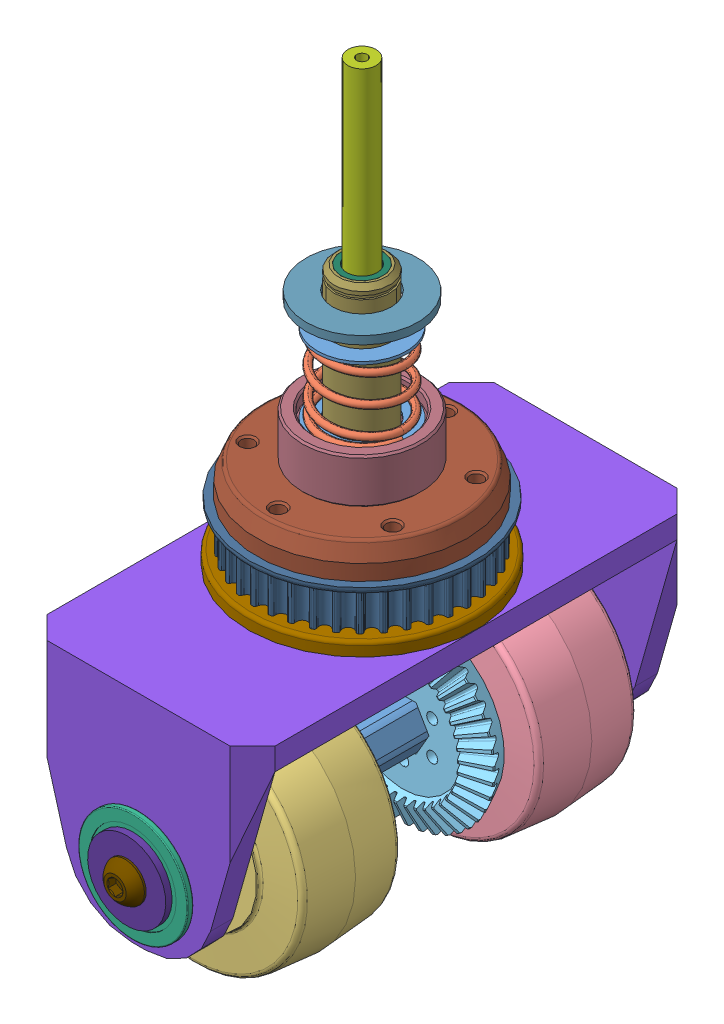
SolidWorks assembly 2018_swerve_module_asm, configuration Default. Lengths in mm.
Overall size (88.48 203.85 142.26).
33 component instances, 26 part files, 0 mates.
Components (placement in the parent):
- 2016_SWERVE_AXLE_RNM_RNM-1: 2016_SWERVE_AXLE_RNM_RNM [Default] x (1 0 0) z (0 0 -1) size (13.74 12.7 127)
- AM-2621_20T_1-25MOD_BEVEL_GEAR-1: AM-2621_20T_1-25MOD_BEVEL_GEAR [Default] at (0 25.321 0) x (1 0 0) z (0 0 -1) size (26.56 18.56 26.56)
- 217-4046-STEP-20141030-1: 217-4046-STEP-20141030 [Default] at (0 0 33.5534) x (0 0 1) z (-1 0 0) size (33.1 63.5 63.5)
- COLSON_WHEEL_MODIFIED-1: COLSON_WHEEL_MODIFIED [Default] at (0 0 -33.5788) x (0 0 1) z (-1 0 0) size (32.43 63.5 63.5)
- AM-2620_40T_1-25MOD_BEVEL_GEAR-1: AM-2620_40T_1-25MOD_BEVEL_GEAR [Default] at (0 0 -13.2049) x (0.866025 -0.5 0) z (-0.5 -0.866025 0) size (50.76 8.78 50.76)
- 217-4006-STEP-20140807-1: 217-4006-STEP-20140807 [Default] at (0 0 61.1187) size (31.12 31.12 7.94)
- 217-4006-STEP-20140807-2: 217-4006-STEP-20140807 [Default] at (0 0 -61.1187) x (-1 0 0) z (0 0 -1) size (31.12 31.12 7.94)
- 8MM_VERT_DRIVE_SHAFT-1: 8MM_VERT_DRIVE_SHAFT [Default] at (0 19.322 0) x (0 1 0) z (0 0 1) size (149.86 8 8)
- SWERVE_SADDLE-1: SWERVE_SADDLE [Default] at (0 38.1 0) x (0 0 1) z (-1 0 0) size (127 62.23 64.77)
- 38T_HTD_PULLEY_AZ_FLANGE-1: 38T_HTD_PULLEY_AZ_FLANGE [Default] at (0 48.26 0) x (0.866025 0 -0.5) z (-0.5 0 -0.866025) size (64.77 3.81 64.77)
- HTD_TB_PULLEY_38T_SWERVE-1: HTD_TB_PULLEY_38T_SWERVE [Default] at (0 59.51 0) x (-0.866025 0 0.5) z (0 -1 0) size (64 64 13)
- SWERVE_PIVOT_HUB_MOUNT-1: SWERVE_PIVOT_HUB_MOUNT [Default] at (0 117.14 0) x (0 -1 0) z (-1 0 0) size (27.43 59.69 59.69)
- SWERVE_PIVOT_HUB_TUBE-1: SWERVE_PIVOT_HUB_TUBE [Default] at (0 118.41 0) x (0 -1 0) z (0 0 1) size (75.56 15.88 15.88)
- TOPHAT_SLEEVE-1: TOPHAT_SLEEVE [Default] at (0 70.277 0) size (33.83 12.7 33.83)
- SWERVE_MOUNTING_HUB-1: SWERVE_MOUNTING_HUB [Default] at (0 109.647 0) x (0 -1 0) z (0 0 1) size (39.37 69.85 69.85) (hidden)
- AL_WASHER-1: AL_WASHER [Default] at (0 109.647 0) size (31.75 2.29 31.75)
- 5905K730_STL_NEEDLE-ROLLER_BRNG-1: 5905K730_STL_NEEDLE-ROLLER_BRNG [Default] at (0 114.41 0) x (1 0 0) z (0 -1 0) size (12 12 8)
- AM_0931-1: AM_0931 [Default] at (0 36.6 0) x (0 1 0) z (0 0 1) size (6 22 22)
- 91525A119-1: 91525A119 [Default] at (0 0 -65.0875) x (0 0 -1) z (0 1 0) size (1.78 22.23 22.23)
- 91525A119-2: 91525A119 [Default] at (0 0 65.0875) x (0 0 1) z (0 1 0) size (1.78 22.23 22.23)
- 98164A211-1: 98164A211 [Default] at (0 0 70.2183) size (11.17 11.22 17.34)
- 98164A211-2: 98164A211 [Default] at (0 0 -70.2183) x (-1 0 0) z (0 0 -1) size (11.17 11.22 17.34)
- STEEL_SHIM_WASHER-1: STEEL_SHIM_WASHER [Default] at (0 79.802 0) size (25.4 0.81 25.4)
- 9657K101_STEEL_COMPRESSION_SPRI-1: 9657K101_STEEL_COMPRESSION_SPRI [Default] at (0 80.6148 0) x (1 0 0) z (0 -1 0) size (25.14 23.85 22.11)
- STEEL_SHIM_WASHER-2: STEEL_SHIM_WASHER [Default] at (0 102.4842 0) size (25.4 0.81 25.4)
- 8MM_SHAFT_44T_HTD_PULLEY_ASM-1: 8MM_SHAFT_44T_HTD_PULLEY_ASM [Default] at (0 146.5405 0) x (-1 0 0) z (0 0 1) size (100.97 27.3 100.97)
  - 8MM_PULLEY_HUB-1: 8MM_PULLEY_HUB [Default] at origin size (22 26.54 19.05) (hidden)
  - HTD_TB_PULLEY_44T-1: HTD_TB_PULLEY_44T [Default] at (0 25.555 0) x (-1 0 0) z (0 -1 0) size (73.91 73.91 16.02) (hidden)
  - 44T_HTD_PULLEY_FLANGE-1: 44T_HTD_PULLEY_FLANGE [Default] at (0 9.5302 0) x (0.5 0 0.866025) z (-0.866025 0 0.5) size (73.91 1.75 73.91) (hidden)
  - 217-2736_20121205_ASM-1: 217-2736_20121205_ASM [Default] at (-4.5154 5.7531 -2.6156) x (-1 0 0) z (0 1 0) size (25.39 25.4 6.35)
    - 217-2736_20121205_1_ASM-1: 217-2736_20121205_1_ASM [Default] at origin size (25.39 25.4 6.35)
      - 217-2736-001_REV1-1-SOLID1-1: 217-2736-001_REV1-1-SOLID1 [Default] at origin size (25.39 25.4 6.35) (hidden)
      - 92185A108-1-SOLID1-1: 92185A108-1-SOLID1 [Default] at origin size (4.65 12.51 4.65) (hidden)
